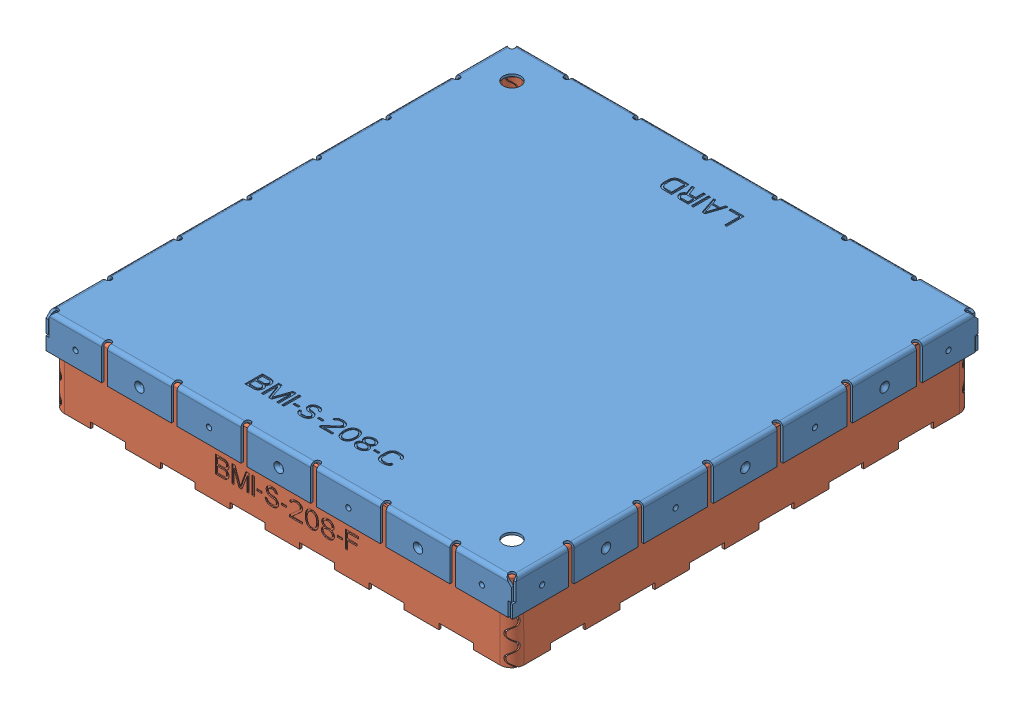
SolidWorks assembly Laird-BMI-S-208-F__AND__BMI-S-208-C, configuration Default. Lengths in mm.
Overall size (41.61 8.64 42.42).
2 component instances, 2 part files, 1 mates.
Components (placement in the parent):
- Laird-DEFAULT_Laird-BMI-S-208-F__and__BMI-S-208-C_BMI-S-208-C-1: Laird-DEFAULT_Laird-BMI-S-208-F__and__BMI-S-208-C_BMI-S-208-C [Default] at (0 20 0) size (40.2 3 40.2)
- Laird-DEFAULT_Laird-BMI-S-208-F__and__BMI-S-208-C_BMI-S-208-F-1: Laird-DEFAULT_Laird-BMI-S-208-F__and__BMI-S-208-C_BMI-S-208-F [Default] at (0 19.8 0) size (41.61 8.64 42.42)
Mates (geometry in assembly coordinates):
- Coincident1: coincident aligned: plane of Laird-DEFAULT_Laird-BMI-S-208-F__and__BMI-S-208-C_BMI-S-208-C-1 through (0 19.8 0) normal (0 -1 0); plane of Laird-DEFAULT_Laird-BMI-S-208-F__and__BMI-S-208-C_BMI-S-208-F-1 through (0 19.8 0) normal (0 -1 0)
